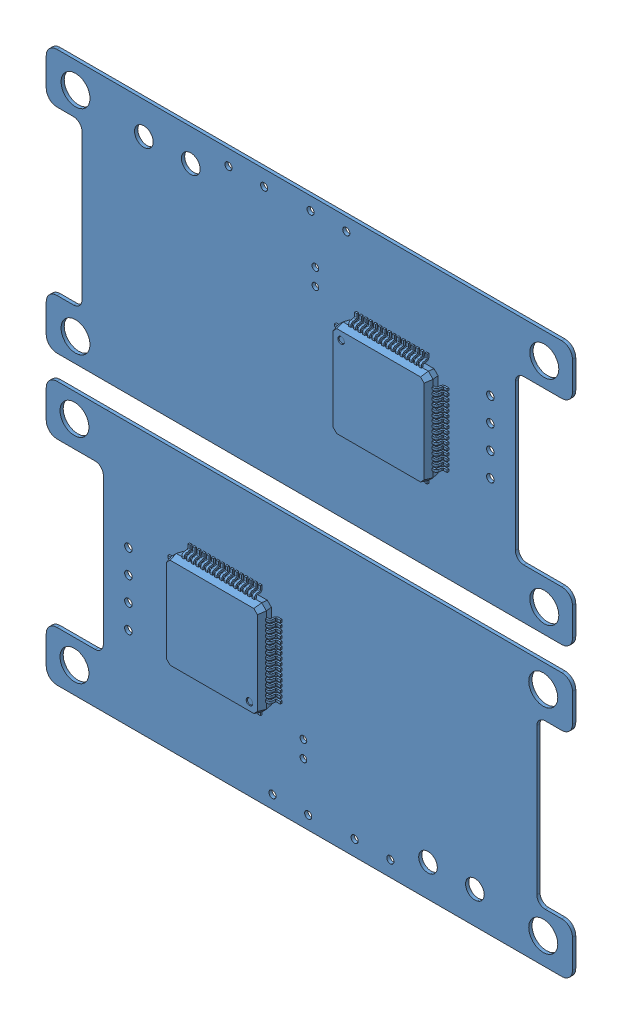
SolidWorks assembly 装配体7, configuration 默认. Lengths in mm.
Overall size (56.13 58.73 1.98).
2 component instances, 1 part files, 2 mates.
Components (placement in the parent):
- 驱动器电路板-1: 驱动器电路板 [默认] at (-173.2693 -89.1537 -0.6431) size (56.13 28.07 1.98)
- 驱动器电路板-2: 驱动器电路板 [默认] at (73.6187 46.6827 -0.6431) x (-1 0 0) z (0 0 1) size (56.13 28.07 1.98)
Mates (geometry in assembly coordinates):
- 重合3: coincident: plane of 驱动器电路板-1 through (-76.7503 -19.9388 -0.6431) normal (0 0 1); plane of ? through (-25.1863 -22.5323 -0.6431) normal (0 0 1)
- 重合5: coincident: plane of assembly; plane of assembly; plane of 驱动器电路板-1 through (-21.7583 -18.7957 -0.9886) normal (1 0 0); plane of 驱动器电路板-2 through (-21.7583 -26.7233 -0.9886) normal (1 0 0)
